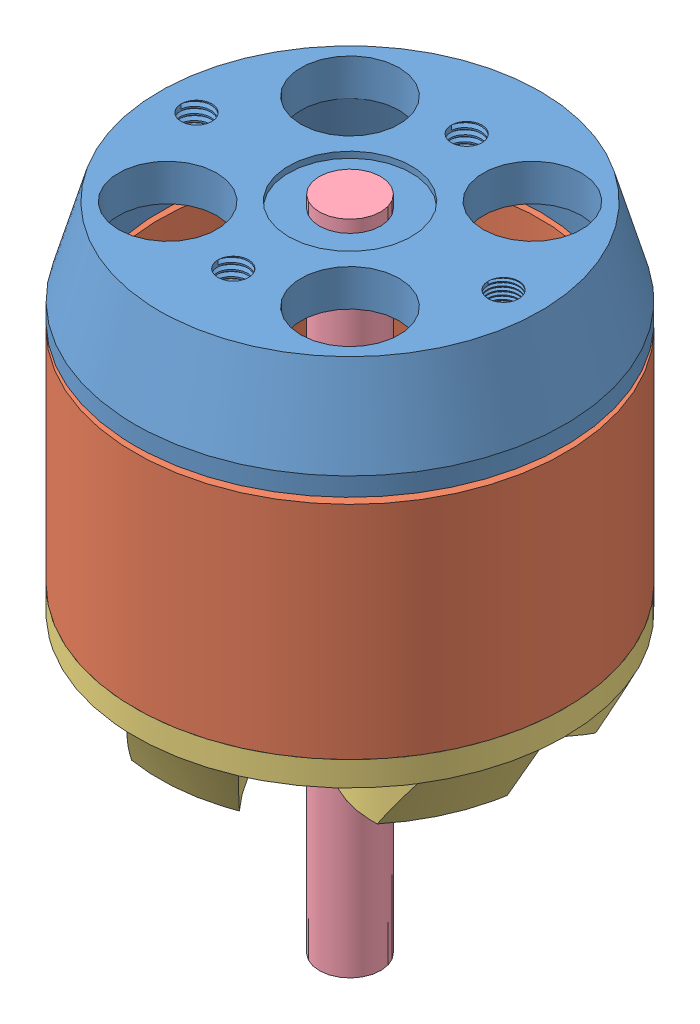
SolidWorks assembly d3536, configuration Default. Lengths in mm.
Overall size (46.45 53.5 46.45).
4 component instances, 4 part files, 6 mates.
Components (placement in the parent):
- bottom_case-1: bottom_case [Default] at (15.7997 3.4433 17.5887) size (35 8.57 35)
- middle_case-1: middle_case [Default] at (15.7997 -15.0567 17.5887) x (-0.998365 0 0.05716) z (-0.05716 0 -0.998365) size (35 18 35)
- top_case-1: top_case [Default] at (15.7997 -15.0567 17.5887) x (-0.907758 0 0.419495) z (0.419495 0 0.907758) size (35 9.5 35)
- shaft-1: shaft [Default] at (15.7997 -41.0567 17.5887) x (-0.024609 0 -0.999697) z (0.999697 0 -0.024609) size (5 53.5 5)
Mates (geometry in assembly coordinates):
- Coincident1: coincident anti-aligned: circle of middle_case-1; circle of top_case-1
- Concentric1: concentric anti-aligned: circle of top_case-1; circle of shaft-1
- Concentric2: concentric aligned: circle of bottom_case-1; circle of shaft-1
- Lock2: lock: unknown of top_case-1; unknown of shaft-1
- Lock3: lock: unknown of middle_case-1; unknown of top_case-1
- Distance3: distance = 0.5 mm anti-aligned: plane of bottom_case-1 through (15.7997 3.4433 17.5887) normal (0 -1 0); plane of middle_case-1 through (15.7997 2.9433 17.5887) normal (0 1 0)
